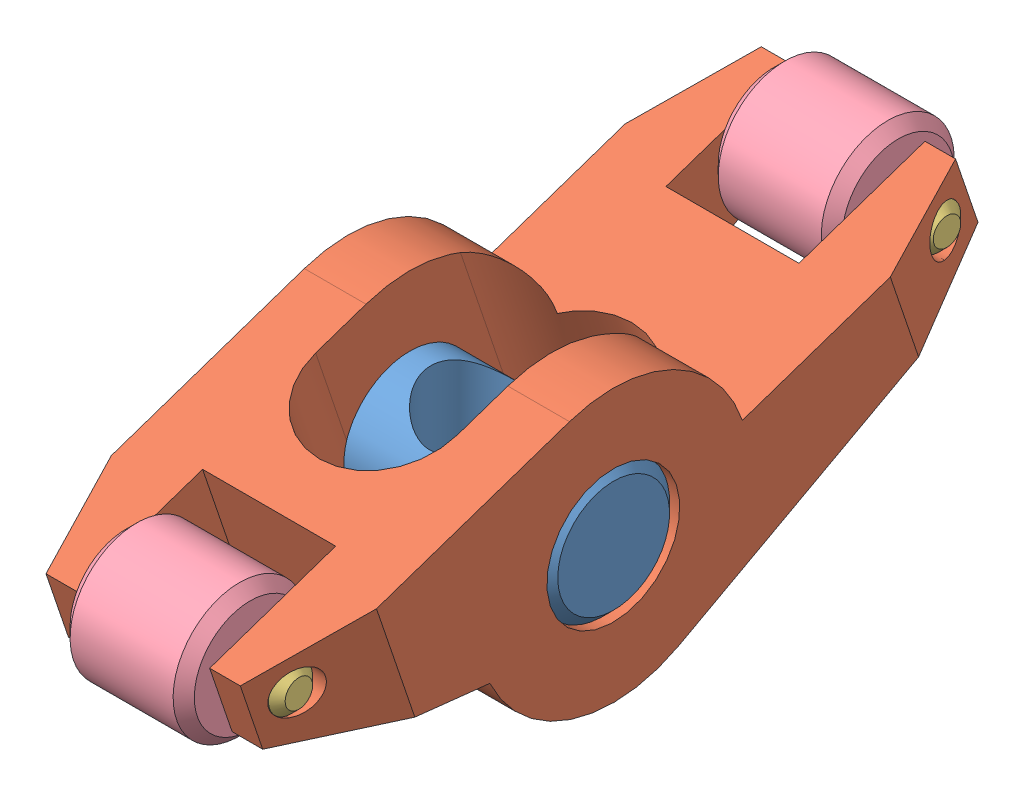
SolidWorks assembly Rocker Arm Assembly, configuration Predeterminado. Lengths in mm.
Overall size (19.05 34.82 57.85).
6 component instances, 4 part files, 10 mates.
Components (placement in the parent):
- Rocker Arm Pin 1-2: Rocker Arm Pin 1 [Predeterminado] at (3.0165 1.1236 19.05) size (19.05 9.53 9.53)
- Rocker Arm-2: Rocker Arm [Predeterminado] at (3.0165 1.1236 19.05) x (1 0 0) z (0 -0.321291 0.946981) size (19 19.53 50.8)
- Rocker Arm Pin 2-2: Rocker Arm Pin 2 [Predeterminado] at (3.0165 1.6409 40.0126) x (0 -1 0) z (0 0 1) size (3.17 15.87 3.17)
- Rocker Arm Roll-2: Rocker Arm Roll [Predeterminado] at (3.0165 7.0831 -6.4207) x (1 0 0) z (0 0.514106 -0.857727) size (8.9 9.53 9.53)
- Rocker Arm Roll-3: Rocker Arm Roll [Predeterminado] at (3.0165 1.6409 40.0126) x (1 0 0) z (0 0.023589 0.999722) size (8.9 9.53 9.53)
- Rocker Arm Pin 2-3: Rocker Arm Pin 2 [Predeterminado] at (3.0165 7.0831 -6.4207) x (0 -0.908094 0.418766) z (0 0.418766 0.908094) size (3.17 15.87 3.17)
Mates (geometry in assembly coordinates):
- Concéntrica2: concentric aligned: cylinder of Rocker Arm Pin 1-2 through (12.5415 1.1236 19.05) axis (-1 0 0) radius 4.765; cylinder of Rocker Arm-2 through (12.5165 1.1236 19.05) axis (-1 0 0) radius 4.765
- Ancho1: width anti-aligned: plane of Rocker Arm Pin 1-2 through (-6.5085 1.1236 19.05) normal (-1 0 0); plane of Rocker Arm-2 through (12.5415 1.1236 19.05) normal (1 0 0); plane of Rocker Arm Pin 1-2 through (12.5165 1.1236 19.05) normal (1 0 0); plane of Rocker Arm-2 through (-6.4835 1.1236 19.05) normal (-1 0 0)
- Concéntrica3: concentric anti-aligned: cylinder of Rocker Arm-2 through (-6.4835 1.6409 40.0126) axis (1 0 0) radius 1.59; cylinder of Rocker Arm Roll-3 through (7.4665 1.6409 40.0126) axis (-1 0 0) radius 4.765
- Ancho2: width aligned: plane of Rocker Arm Roll-3 through (7.4665 1.6409 40.0126) normal (1 0 0); plane of Rocker Arm-2 through (-1.4335 1.6409 40.0126) normal (-1 0 0); plane of Rocker Arm Roll-3 through (-1.7485 -12.2024 27.9345) normal (1 0 0); plane of Rocker Arm-2 through (7.7815 -12.2024 27.9345) normal (-1 0 0)
- Concéntrica4: concentric anti-aligned: cylinder of Rocker Arm-2 through (-6.4835 7.0831 -6.4207) axis (1 0 0) radius 1.59; cylinder of Rocker Arm Roll-2 through (7.4665 7.0831 -6.4207) axis (-1 0 0) radius 4.765
- Ancho3: width aligned: plane of Rocker Arm Roll-2 through (-1.4335 7.0831 -6.4207) normal (-1 0 0); plane of Rocker Arm-2 through (7.4665 7.0831 -6.4207) normal (1 0 0); plane of Rocker Arm Roll-2 through (7.7815 -2.0047 -2.1226) normal (-1 0 0); plane of Rocker Arm-2 through (-1.7485 -2.0047 -2.1226) normal (1 0 0)
- Concéntrica5: concentric anti-aligned: cylinder of Rocker Arm-2 through (-6.4835 1.6409 40.0126) axis (1 0 0) radius 1.59; cylinder of Rocker Arm Pin 2-2 through (10.9515 1.6409 40.0126) axis (-1 0 0) radius 1.585
- Ancho4: width aligned: plane of Rocker Arm Pin 2-2 through (-4.9185 1.6409 40.0126) normal (-1 0 0); plane of Rocker Arm-2 through (10.9515 1.6409 40.0126) normal (1 0 0); plane of Rocker Arm Pin 2-2 through (7.7815 -12.2024 27.9345) normal (-1 0 0); plane of Rocker Arm-2 through (-1.7485 -12.2024 27.9345) normal (1 0 0)
- Concéntrica6: concentric anti-aligned: cylinder of Rocker Arm-2 through (-6.4835 7.0831 -6.4207) axis (1 0 0) radius 1.59; cylinder of Rocker Arm Pin 2-3 through (10.9515 7.0831 -6.4207) axis (-1 0 0) radius 1.585
- Ancho5: width anti-aligned: plane of Rocker Arm Pin 2-3 through (-4.9185 7.0831 -6.4207) normal (-1 0 0); plane of Rocker Arm-2 through (10.9515 7.0831 -6.4207) normal (1 0 0); plane of Rocker Arm Pin 2-3 through (-1.7485 -2.0047 -2.1226) normal (1 0 0); plane of Rocker Arm-2 through (7.7815 -2.0047 -2.1226) normal (-1 0 0)
